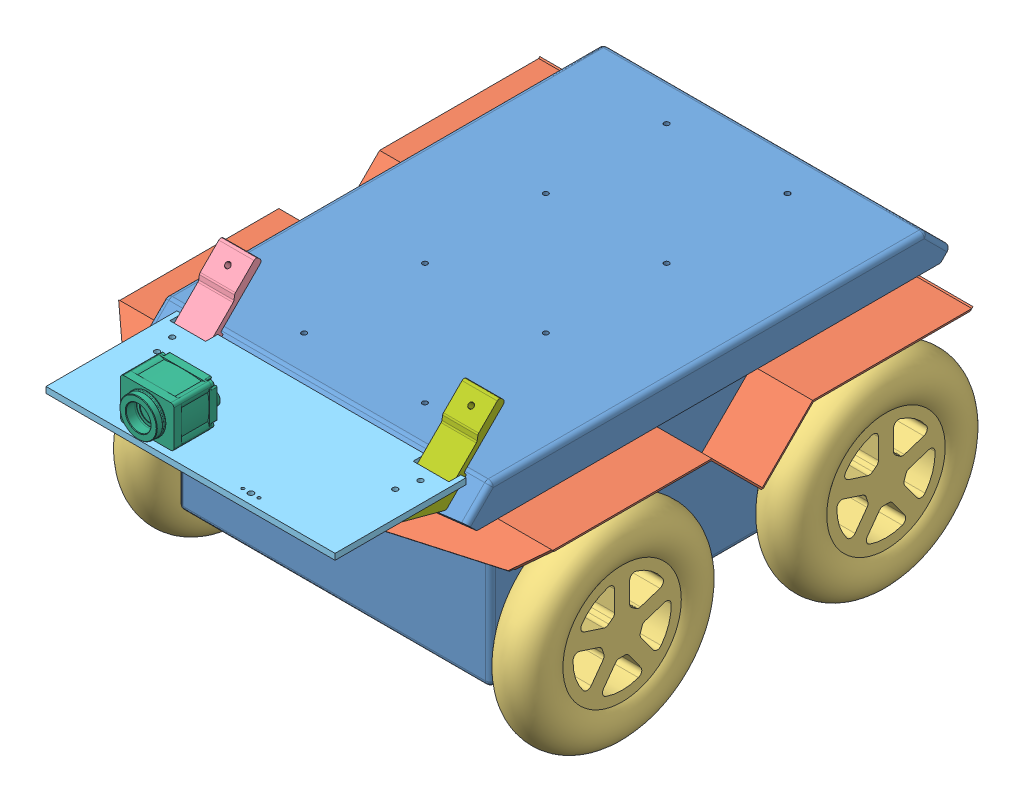
SolidWorks assembly Jackal UGV 3D Model, configuration Default. Lengths in mm.
Overall size (430 295.99 607.92).
11 component instances, 7 part files, 1 mates.
Components (placement in the parent):
- Simplified Model Base-1: Simplified Model Base [Default] at origin size (337.59 184 494.34)
- Simplified Model Fenders-1: Simplified Model Fenders [Default] at origin size (430 52.25 503.1)
- Simplified Wheel-1: Simplified Wheel [Default] at (187.7938 100 131) x (0 0 -1) z (1 0 0) size (200 200 50)
- Simplified Wheel-2: Simplified Wheel [Default] at (187.7938 100 -131) x (0 0 -1) z (1 0 0) size (200 200 50)
- Simplified Wheel-3: Simplified Wheel [Default] at (-187.7938 100 -131) x (0 0 -1) z (1 0 0) size (200 200 50)
- Simplified Wheel-4: Simplified Wheel [Default] at (-187.7938 100 131) x (0 0 -1) z (1 0 0) size (200 200 50)
- CameraMountPlate-1: CameraMountPlate [Default] at (-125.7466 201.8468 140.6963) size (287 68.99 175.19)
  - Bracket-1: Bracket [Default] at (-10.8339 54.0228 74.591) size (35 68.99 103.19)
  - Plate-1: Plate [Default] at (127.4161 42.0124 148.6725) size (287 6 130)
  - UI-5260FA-C-HQ-1: UI-5260FA-C-HQ [Default] at (77.4161 68.5124 206.6725) size (53 41 63.3)
  - MirrorBracket-5: MirrorBracket [Default] at (265.6661 54.0228 74.591) x (-1 0 0) z (0 0 -1) size (35 68.99 103.19)
Mates (geometry in assembly coordinates):
- Coincident1: coincident anti-aligned: plane of Simplified Model Base-1 through (-156.786 215.5 250) normal (0 0.707107 0.707107); plane of CameraMountPlate-1/MirrorBracket-5 through (104.9195 247.0307 218.4693) normal (0 -0.707107 -0.707107)
